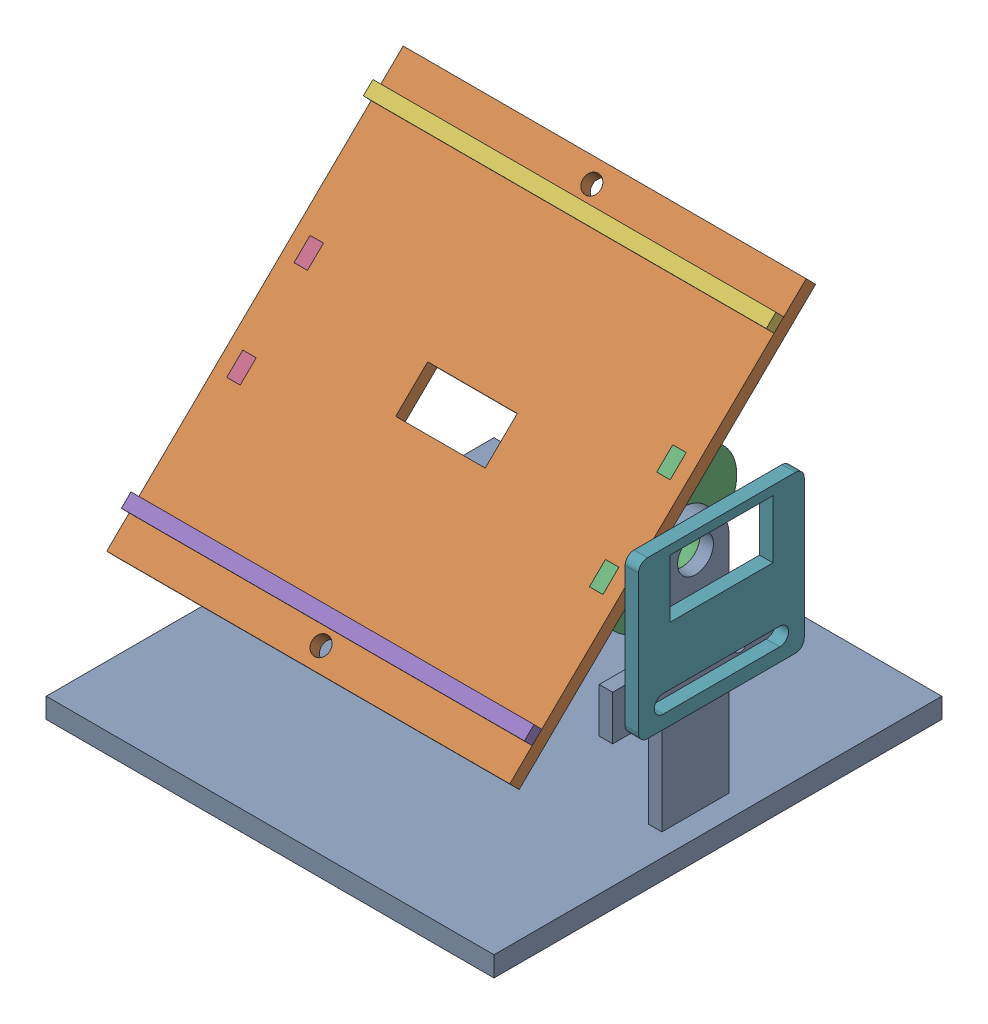
SolidWorks assembly Assem6, configuration Default. Lengths in mm.
Overall size (100 95.39 100).
7 component instances, 5 part files, 18 mates.
Components (placement in the parent):
- stand-1: stand [Default] at origin size (100 62 100)
- base-1: base [Default] at (0 60.941 6.286) x (1 0 0) z (0 -0.698445 0.715663) size (90 3 92.5)
- hole-1: hole [Default] at (39 55.5735 1.0477) x (0 -0.698445 0.715663) z (1 0 0) size (34 18 3)
- hole-2: hole [Default] at (-42 55.5735 1.0477) x (0 -0.698445 0.715663) z (1 0 0) size (34 18 3)
- boundry-1: boundry [Default] at (0 39.5585 36.0703) x (1 0 0) z (0 -0.698445 0.715663) size (90 5.5 3)
- boundry-2: boundry [Default] at (0 92.2911 -17.9623) x (1 0 0) z (0 -0.698445 0.715663) size (90 5.5 3)
- bracket-1: bracket [Default] at (48 44.6454 -2.7886) x (0 0 1) z (0 -1 0) size (37 3 35)
Mates (geometry in assembly coordinates):
- Parallel1: parallel aligned: plane of hole-1 through (42 55.5735 1.0477) normal (1 0 0)
- Concentric1: concentric aligned: circle of hole-1; circle of stand-1
- Parallel3: parallel anti-aligned: plane of base-1 through (0 63.088 8.3813) normal (0 0.715663 0.698445); plane of boundry-1 through (30 33.527 34.3758) normal (0 -0.715663 -0.698445)
- Parallel4: parallel anti-aligned: plane of base-1 through (0 63.088 8.3813) normal (0 0.715663 0.698445); plane of boundry-2 through (-20 86.2596 -19.6568) normal (0 -0.715663 -0.698445)
- Coincident1: coincident anti-aligned: line of base-1 through (42 68.6755 2.656) axis (0 0.698445 -0.715663); line of hole-1 through (42 72.1678 -0.9223) axis (0 -0.698445 0.715663)
- Coincident2: coincident anti-aligned: line of base-1 through (39 68.6755 2.656) axis (1 0 0); line of hole-1 through (42 68.6755 2.656) axis (-1 0 0)
- Coincident3: coincident aligned: line of base-1 through (-39 72.1678 -0.9223) axis (-1 0 0); line of hole-2 through (-39 72.1678 -0.9223) axis (-1 0 0)
- Coincident5: coincident anti-aligned: line of base-1 through (-39 68.6755 2.656) axis (0 0.698445 -0.715663); line of hole-2 through (-39 72.1678 -0.9223) axis (0 -0.698445 0.715663)
- Parallel5: parallel anti-aligned: plane of base-1 through (0 63.088 8.3813) normal (0 0.715663 0.698445); plane of boundry-2 through (-20 86.2596 -19.6568) normal (0 -0.715663 -0.698445)
- Coincident7: coincident anti-aligned: line of base-1 through (-30 88.355 -21.8038) axis (0 -0.698445 0.715663); line of boundry-2 through (-30 86.2596 -19.6568) axis (0 0.698445 -0.715663)
- Coincident8: coincident anti-aligned: line of base-1 through (-20 88.355 -21.8038) axis (-1 0 0); line of boundry-2 through (-30 88.355 -21.8038) axis (1 0 0)
- Parallel6: parallel anti-aligned: plane of base-1 through (0 63.088 8.3813) normal (0 0.715663 0.698445); plane of boundry-1 through (-20 33.527 34.3758) normal (0 -0.715663 -0.698445)
- Coincident9: coincident anti-aligned: line of base-1 through (-20 35.6223 32.2288) axis (-1 0 0); line of boundry-1 through (-30 35.6223 32.2288) axis (1 0 0)
- Coincident10: coincident anti-aligned: line of base-1 through (-30 35.6223 32.2288) axis (0 -0.698445 0.715663); line of boundry-1 through (-30 33.527 34.3758) axis (0 0.698445 -0.715663)
- Coincident13: coincident anti-aligned: plane of stand-1 through (42 64.5 7.5) normal (-1 0 0); plane of hole-1 through (42 55.5735 1.0477) normal (1 0 0)
- Parallel7: parallel anti-aligned: plane of stand-1 through (45 64.5 7.5) normal (1 0 0); plane of bracket-1 through (45 44.6454 -2.7886) normal (-1 0 0)
- Coincident14: coincident anti-aligned: plane of stand-1 through (45 64.5 7.5) normal (1 0 0); plane of bracket-1 through (45 44.6454 -2.7886) normal (-1 0 0)
- Parallel8: parallel anti-aligned: plane of bracket-1 through (45 27.1454 -21.2886) normal (0 0 -1)
